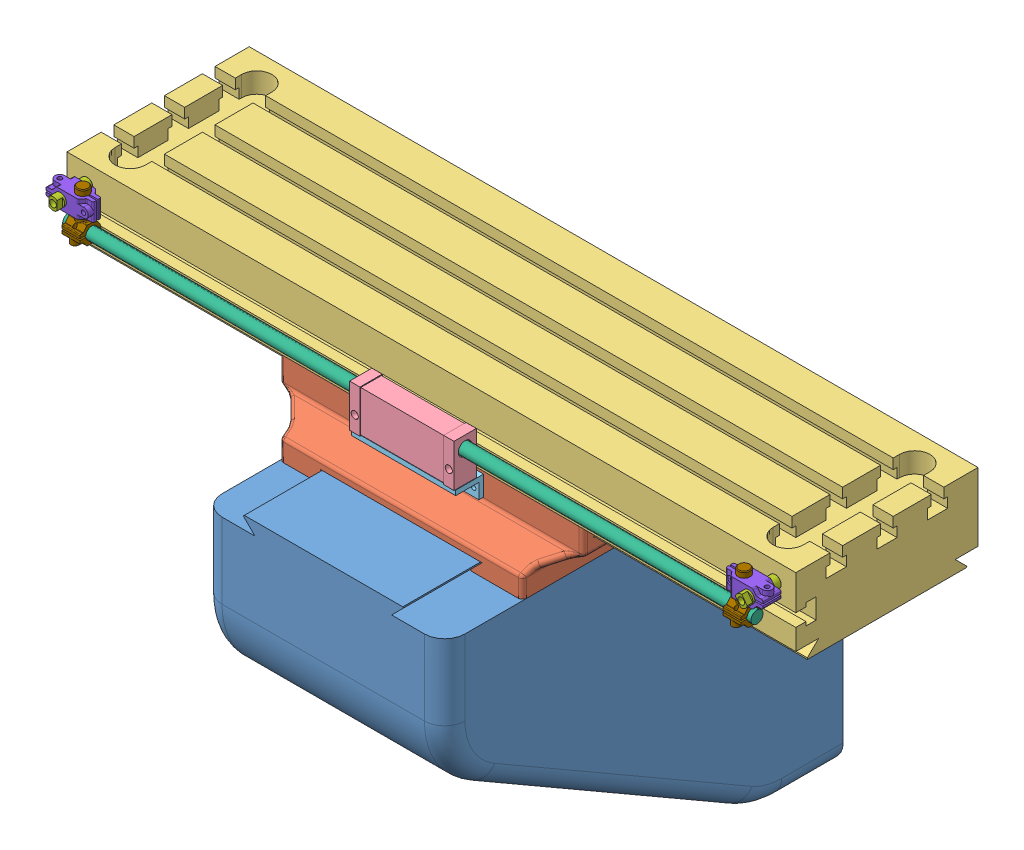
SolidWorks assembly mill, configuration Default. Lengths in mm.
Overall size (914.4 544.86 500).
12 component instances, 9 part files, 24 mates.
Components (placement in the parent):
- knee-1: knee [Default] at origin size (304.8 396.88 500)
- saddle-1: saddle [Default] at (0 0 250) x (-1 0 0) z (0 0 -1) size (381 78.14 304.8)
- table-1: table [Default] at (0 163.8649 250) size (914.4 101.6 228.6)
- head-1: head [Default] at (-0.6553 101.8899 386.8081) size (131 53.5 28)
- bracket-1: bracket [Default] at (0 75.1399 364.3) size (131 25 35)
- scale-1: scale [Default] at (-0.75 113.8899 386.8081) x (1 0 0) z (0 -0.116286 0.993216) size (863.6 15.2 15.2)
- pillar-3: pillar [Default] at (431.8 141.8649 364.3) x (0.803991 0.594642 0) z (0.594642 -0.803991 0) size (15 57 15)
- pillar-4: pillar [Default] at (-431.8 141.8649 364.3) x (1 0 0) z (0 -1 0) size (15 57 15)
- clamp-1: clamp [Default] at (423.3 141.8649 386.8081) size (53 22.5 22.5)
- pin-1: pin [Long] at (414.8 113.8899 386.8081) x (0 0 1) z (0 1 0) size (26.25 22.5 57.5)
- clamp-2: clamp [Default] at (-423.3 141.8649 386.8081) x (1 0 0) z (0 -1 0) size (53 22.5 22.5)
- pin-2: pin [Long] at (-414.8 113.8899 386.8081) x (0 0 1) z (0 1 0) size (26.25 22.5 57.5)
Mates (geometry in assembly coordinates):
- Coincident1: coincident anti-aligned: plane of knee-1 through (101.6 15.875 500) normal (0 1 0); plane of saddle-1 through (101.6 15.875 -495.055) normal (0 -1 0)
- Coincident2: coincident anti-aligned: plane of knee-1 through (-101.6 15.875 500) normal (-0.707107 -0.707107 0); plane of saddle-1 through (-101.6 15.875 -495.055) normal (0.707107 0.707107 0)
- Coincident3: coincident anti-aligned: plane of saddle-1 through (-808.555 62.2649 148.4) normal (0 1 0); plane of table-1 through (457.2 62.2649 351.6) normal (0 -1 0)
- Coincident4: coincident anti-aligned: plane of saddle-1 through (-808.555 62.2649 351.6) normal (0 -0.707107 -0.707107); plane of table-1 through (457.2 78.1399 335.725) normal (0 0.707107 0.707107)
- Table Lock: coincident anti-aligned: plane of saddle-1 through (0 0 250) normal (-1 0 0); plane of table-1 through (0 163.8649 250) normal (1 0 0)
- Saddle Lock: distance = 250 mm anti-aligned: plane of assembly through (0 0 0) normal (0 0 1); plane of saddle-1 through (0 0 250) normal (0 0 -1)
- Coincident7: coincident anti-aligned: plane of saddle-1 through (190.5 78.1399 364.3) normal (0 0 1); plane of bracket-1 through (-65.5 75.1399 364.3) normal (0 0 -1)
- Distance2: distance = 3 mm aligned: plane of saddle-1 through (190.5 78.1399 135.7) normal (0 1 0); plane of bracket-1 through (-65.5 75.1399 370.3) normal (0 1 0)
- Coincident9: coincident anti-aligned: plane of saddle-1 through (0 0 250) normal (-1 0 0); plane of bracket-1 through (0 75.1399 364.3) normal (1 0 0)
- Coincident10: coincident anti-aligned: plane of head-1 through (-66.1553 75.1399 400.8081) normal (0 -1 0); plane of bracket-1 through (-65.5 75.1399 370.3) normal (0 1 0)
- Concentric1: concentric aligned: cylinder of head-1 through (59 75.1399 383.8081) axis (0 -1 0) radius 2.1; cylinder of bracket-1 through (59 69.1399 383.8081) axis (0 -1 0) radius 2.75
- Parallel1: parallel aligned: plane of saddle-1 through (190.5 78.1399 364.3) normal (0 0 1); plane of head-1 through (-53.1553 76.1399 399.8081) normal (0 0 1)
- Concentric2: concentric aligned: cylinder of head-1 through (64.8447 113.8899 386.8081) axis (-1 0 0) radius 7.6; cylinder of scale-1 through (431.05 113.8899 386.8081) axis (-1 0 0) radius 7.6
- Concentric41: concentric aligned: cylinder of table-1 through (431.8 141.8649 364.3) axis (0 0 1) radius 3.5; cylinder of pillar-3 through (431.8 141.8649 350.3) axis (0 0 1) radius 4
- Coincident111: coincident anti-aligned: plane of table-1 through (-457.2 78.1399 364.3) normal (0 0 1); plane of pillar-3 through (431.8 141.8649 364.3) normal (0 0 -1)
- Concentric51: concentric aligned: cylinder of table-1 through (-431.8 141.8649 364.3) axis (0 0 1) radius 3.5; cylinder of pillar-4 through (-431.8 141.8649 350.3) axis (0 0 1) radius 4
- Coincident121: coincident anti-aligned: plane of table-1 through (-457.2 78.1399 364.3) normal (0 0 1); plane of pillar-4 through (-431.8 141.8649 364.3) normal (0 0 -1)
- Concentric7: concentric aligned: cylinder of pillar-3 through (431.8 141.8649 407.3) axis (0 0 -1) radius 7.5; cylinder of clamp-1 through (431.8 141.8649 471.3825) axis (0 0 -1) radius 7.5
- Concentric8: concentric anti-aligned: cylinder of clamp-1 through (414.8 57.2905 386.8081) axis (0 1 0) radius 7.5; cylinder of pin-1 through (414.8 160.1399 386.8081) axis (0 -1 0) radius 7.5
- Concentric9: concentric aligned: cylinder of scale-1 through (431.05 113.8899 386.8081) axis (-1 0 0) radius 7.6; cylinder of pin-1 through (426.05 113.8899 386.8081) axis (-1 0 0) radius 7.6
- Distance3: distance = 5 mm aligned: plane of scale-1 through (431.05 113.8899 386.8081) normal (1 0 0); plane of pin-1 through (426.05 113.8899 386.8081) normal (1 0 0)
- Concentric13: concentric anti-aligned: cylinder of pillar-4 through (-431.8 141.8649 407.3) axis (0 0 -1) radius 7.5; cylinder of clamp-2 through (-431.8 141.8649 302.2337) axis (0 0 1) radius 7.5
- Concentric14: concentric anti-aligned: cylinder of clamp-2 through (-414.8 57.2905 386.8081) axis (0 1 0) radius 7.5; cylinder of pin-2 through (-414.8 160.1399 386.8081) axis (0 -1 0) radius 7.5
- Concentric15: concentric aligned: cylinder of scale-1 through (431.05 113.8899 386.8081) axis (-1 0 0) radius 7.6; cylinder of pin-2 through (-403.55 113.8899 386.8081) axis (-1 0 0) radius 7.6
